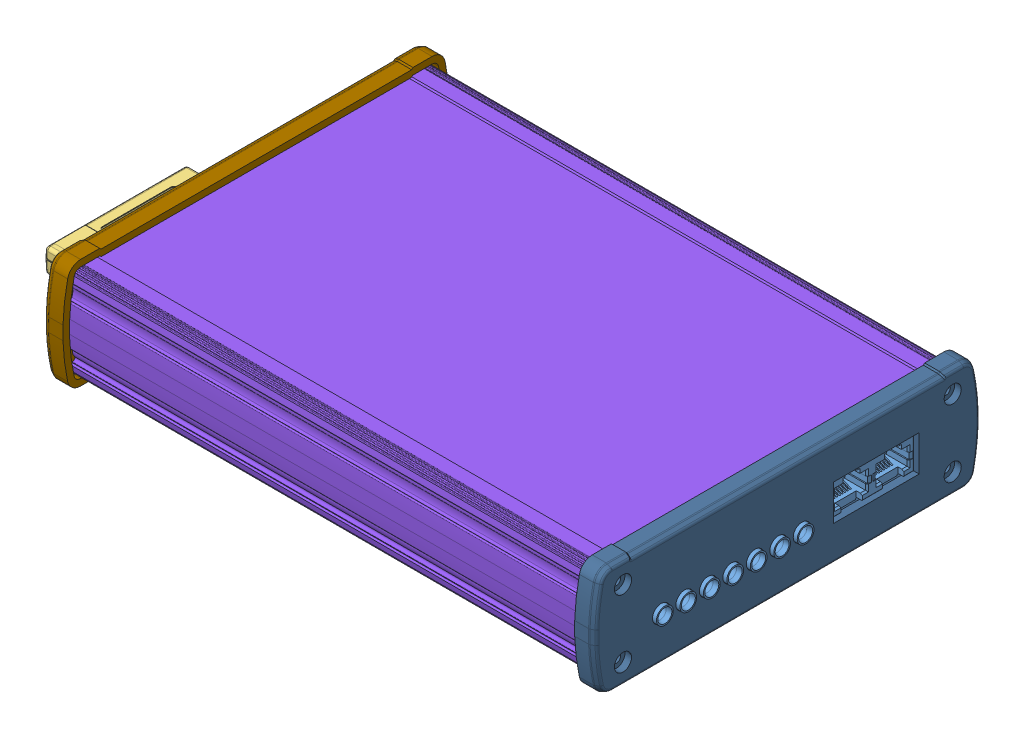
SolidWorks assembly PRiME_PSA, configuration Default. Lengths in mm.
Overall size (232.7 41.6 146.6).
20 component instances, 11 part files, 5 mates.
Components (placement in the parent):
- PRiME_Preamp-1: PRiME_Preamp [Default] at (196.012 -24.25 -5.103) size (215.67 21.29 129.79)
  - MW_PRiME-MB-1: MW_PRiME-MB [Default] at origin size (212.12 17.21 129.79)
    - PRiME-MB-2: PRiME-MB [Default] at (-192.4001 -1.6 0) x (1 0 0) z (0 1 0) size (212.12 129.79 17.21)
  - MW_PRiME_PowerModule-1: MW_PRiME_PowerModule [Default] at (-196.5901 11.067 -10.66) x (0 0 1) z (-1 0 0) size (67.31 17.07 76.5)
    - PRiME_PowerModule-1: PRiME_PowerModule [Default] at (-67.31 -1.6 0) x (1 0 0) z (0 1 0) size (67.31 76.5 17.07)
  - CC2300_nominal-2: CC2300_nominal [Default] at (-138.8772 2.6328 -43.6707) x (0 0 -1) z (1 0 0) size (54 9.11 86.51)
  - MW_PRiME_HFModule-2: MW_PRiME_HFModule [Default] at (-71.7501 11.14 -76.2) x (-1 0 0) z (0 0 -1) size (50.8 12.58 69.85)
    - PRiME_HFModule-1: PRiME_HFModule [Default] at (-50.8 -1.6 0) x (1 0 0) z (0 1 0) size (50.8 69.85 12.58)
  - MW_PRiME_PressureModule-2: MW_PRiME_PressureModule [Default] at (-71.7501 11.14 -117.48) x (-1 0 0) z (0 0 -1) size (38.1 11.66 38.1)
    - PRiME_PressureModule-1: PRiME_PressureModule [Default] at (-38.1 -1.6 0) x (1 0 0) z (0 1 0) size (38.1 38.1 11.66)
  - MW_PRiME_ECGModule-2: MW_PRiME_ECGModule [Default] at (-125.7201 11.067 -114.31) x (-1 0 0) z (0 0 -1) size (50.8 13.5 107.95)
    - PRiME_ECGModule-1: PRiME_ECGModule [Default] at (-50.8 -1.6 0) x (1 0 0) z (0 1 0) size (50.8 107.95 13.5)
  - MW_PRiME_ADCModule-2: MW_PRiME_ADCModule [Default] at (-167.0001 11.067 -117.48) x (-1 0 0) z (0 0 -1) size (38.1 12.15 34.92)
    - PRiME_ADCModule-2: PRiME_ADCModule [Default] at (-38.1 -1.6 0) x (1 0 0) z (0 1 0) size (38.1 34.92 12.15)
- hbexn23362-1: hbexn23362 [Default] at (200 615.116 -712.2521) x (0 0 1) z (-1 0 0) size (146.6 41.6 7.5)
  - EXN-23362M-B-1: EXN-23362M-B [Default] at origin size (140 35.42 200.01)
  - EXN-23362M-P-1: EXN-23362M-P [Default] at (312.1179 -644.6848 161) size (146.6 41.6 7.5)
  - EXN-23362M-P_Right-1: EXN-23362M-P_Right [Default] at (972.3862 -644.6848 39) x (-1 0 0) z (0 0 -1) size (146.6 41.6 7.5)
  - EXN-23383-GSK-1: EXN-23383-GSK [Default] at (312.1179 -644.6848 -31) size (141.2 36.2 3) (hidden)
  - EXN-23383-GSK-2: EXN-23383-GSK [Default] at (312.1179 -644.6848 168) size (141.2 36.2 3) (hidden)
Mates (geometry in assembly coordinates):
- Coincident1: coincident anti-aligned: plane of hbexn23362-1/EXN-23362M-B-1 through (0 615.116 -712.2521) normal (-1 0 0); plane of assembly through (0 0 0) normal (1 0 0)
- Coincident2: coincident aligned: plane of hbexn23362-1/EXN-23362M-B-1 through (0 0 -712.2521) normal (0 1 0); plane of assembly through (0 0 0) normal (0 1 0)
- Coincident3: coincident aligned: plane of hbexn23362-1/EXN-23362M-B-1 through (0 615.116 0) normal (0 0 1); plane of assembly through (0 0 0) normal (0 0 1)
- Coincident4: coincident anti-aligned: plane of PRiME_Preamp-1/MW_PRiME-MB-1 through (196.012 -25.85 -5.103) normal (0 -1 0); plane of hbexn23362-1/EXN-23362M-B-1 through (0 -25.85 -712.2521) normal (0 1 0)
- Coincident5: coincident: plane of PRiME_Preamp-1/MW_PRiME-MB-1 through (196.012 -24.25 -70) normal (0 0 1); moEndPointRef_w of hbexn23362-1/EXN-23362M-B-1
